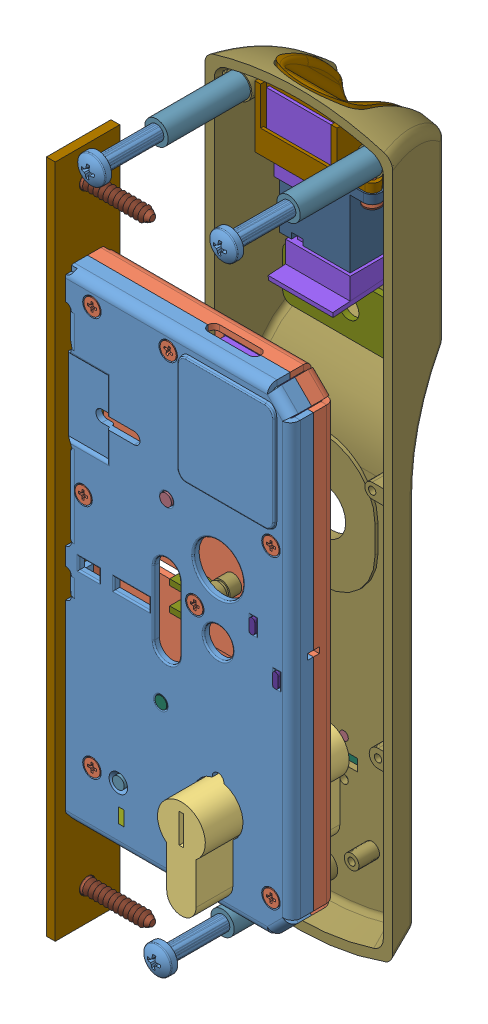
SolidWorks assembly porte, configuration Défaut. Lengths in mm.
Overall size (273.47 400 77.87).
74 component instances, 43 part files, 45 mates.
Components (placement in the parent):
- capteur-1: capteur [Défaut] at (-59.4622 -33.5309 -3.2336) x (0.307692 -0.951486 0) z (-0.951486 -0.307692 0) size (14.18 5.77 12.92)
  - piece26-1: piece26 [Défaut] at (1.6738 0.6186 2.775) size (12.75 5.77 7.15)
  - piece 28-1: piece 28 [Défaut] at (1.6738 0.6186 0.775) size (12.75 5.77 5.95)
  - piece27-2: piece27 [Défaut] at (-0.2012 0.6186 2.975) size (1 2.8 4.5)
  - piece29-1: piece29 [Défaut] at (-3.3489 0.6186 5.3357) x (0.986417 0 0.164259) z (-0.164259 0 0.986417) size (13.3 5.06 1.9)
- Assemblage9-1: Assemblage9 [Défaut] at (-68.5121 32.669 3.5) x (0 1 0) z (0 0 -1) size (37.07 29 14.01)
  - Pièce31-1: Pièce31 [Défaut] at (-136.852 -20.6482 -3) size (37.07 29 6.5)
  - Assemblage8-1: Assemblage8 [Défaut] at (10.8904 0.9488 3.6462) x (0 0 1) z (0 1 0) size (12.77 25.8 12.77)
    - piece 33-1: piece 33 [Défaut] at (-0.2667 2.2913 0) size (11 9 11)
    - piece32-1: piece32 [Défaut] at (-0.2667 2.2913 0) x (-0.176766 0 0.984253) z (-0.984253 0 -0.176766) size (11 19.8 11)
  - Pièce30-1: Pièce30 [Défaut] at (-136.852 22.3518 10) x (1 0 0) z (0 0 -1) size (37.07 29 14)
- tetiere-1: tetiere [Défaut] at (-124.6604 -27.8986 -47.7834) x (0 0 -1) z (1 0 0) size (22 230 25.2)
  - tetiere-1: tetiere [Défaut] at (-47.7834 3.4752 0) size (22 230 6)
  - Pièce37-1: Pièce37 [Défaut] at (-8.0012 83.4752 -19.368) x (1 0 0) z (0 -1 0) size (11 12 10)
  - Pièce37-2: Pièce37 [Défaut] at (-8.0012 -52.5248 -19.368) x (1 0 0) z (0 -1 0) size (11 12 10)
  - vis F90 M5-25-1: vis F90 M5-25 [PreviewCfg] at (-47.7834 107.4752 -1.3) x (0 0 1) z (-1 0 0) size (25 9.3 9.3)
  - vis F90 M5-25-2: vis F90 M5-25 [PreviewCfg] at (-47.7834 -100.5248 -1.3) x (0 0 1) z (-1 0 0) size (25 9.3 9.3)
- Assemblage5-1: Assemblage5 [Défaut] at (-67.1198 -31.1461 -5) x (0 1 0) z (0 0 1) size (150 70 16.5)
  - Pièce20-1: Pièce20 [Défaut] at (81.7227 21.0405 -3.5) x (0 0 1) z (-1 0 0) size (14 6 6)
  - Pièce20-2: Pièce20 [Défaut] at (41.7227 -13.9595 -3.5) x (0 0 1) z (-1 0 0) size (14 6 6)
  - Pièce20-3: Pièce20 [Défaut] at (24.7227 50.0405 -3.5) x (0 0 1) z (-1 0 0) size (14 6 6)
  - Pièce20-4: Pièce20 [Défaut] at (11.2227 11.9905 -3.5) x (0 0 1) z (-0.071229 0.99746 0) size (14 6 6)
  - Pièce20-5: Pièce20 [Défaut] at (-62.2773 -13.9595 -3.5) x (0 0 1) z (-1 0 0) size (14 6 6)
  - Pièce21-1: Pièce21 [Défaut] at (37.7227 21.5405 -3.5) x (0 0 1) z (-1 0 0) size (16.4 6 6)
  - Pièce23-1: Pièce23 [Défaut] at (-54.2773 38.0405 -3.5) x (0 0 1) z (-1 0 0) size (16 6 6)
  - Pièce22-2: Pièce22 [Défaut] at (-23.2773 23.5405 -3.5) x (0 0 1) z (-0.988921 -0.148442 0) size (16 6 6)
  - Pièce24-1: Pièce24 [Défaut] at (3.7227 19.5405 3) x (-1 0 0) z (0 0 -1) size (10 9 9.5)
  - Pièce25-1: Pièce25 [Défaut] at (-74.2773 -20.9595 -0.5) size (28 10 16)
  - Pièce38-1: Pièce38 [Défaut] at (65.7227 21.0405 -3.5) x (0 0 1) z (-1 0 0) size (9 6 6)
- Pièce18-1: Pièce18 [Défaut] at (-46.1604 57.5766 7.5) x (0 -1 0) z (0 0 -1) size (163.01 77.21 8.5)
- vis1-1: vis1 [ISO 7046-1 - M3 x 6 - Z --- 6C] at (-114.1604 50.5766 -7.5) x (0 0 1) z (0 -1 0) size (6 5.5 5.5)
- vis1-2: vis1 [ISO 7046-1 - M3 x 6 - Z --- 6C] at (-114.1604 -85.4234 -7.5) x (0 0 1) z (0.484646 -0.87471 0) size (6 5.5 5.5)
- vis1-3: vis1 [ISO 7046-1 - M3 x 6 - Z --- 6C] at (-53.1604 10.5766 7.5) x (0 0 -1) z (0 1 0) size (6 5.5 5.5)
- vis1-4: vis1 [ISO 7046-1 - M3 x 6 - Z --- 6C] at (-53.1604 -93.4234 7.5) x (0 0 -1) z (0 1 0) size (6 5.5 5.5)
- vis1-5: vis1 [ISO 7046-1 - M3 x 6 - Z --- 6C] at (-88.1604 50.5766 7.5) x (0 0 -1) z (-0.949467 0.313867 0) size (6 5.5 5.5)
- vis1-6: vis1 [ISO 7046-1 - M3 x 6 - Z --- 6C] at (-117.1604 -6.4234 7.5) x (0 0 -1) z (0 1 0) size (6 5.5 5.5)
- vis1-7: vis1 [ISO 7046-1 - M3 x 6 - Z --- 6C] at (-114.1604 -85.4234 7.5) x (0 0 -1) z (0 1 0) size (6 5.5 5.5)
- vis1-8: vis1 [ISO 7046-1 - M3 x 6 - Z --- 6C] at (-114.1604 50.5766 7.5) x (0 0 -1) z (0 1 0) size (6 5.5 5.5)
- vis1-9: vis1 [ISO 7046-1 - M3 x 6 - Z --- 6C] at (-79.1104 -19.9234 7.5) x (0 0 -1) z (0 1 0) size (6 5.5 5.5)
- vis2-1: vis2 [ISO 7045 - M2 x 8 - Z --- 8N] at (-61.1604 -32.4234 1.87) x (0 0 -1) z (0 1 0) size (9.57 4 4)
- vis2-2: vis2 [ISO 7045 - M2 x 8 - Z --- 8N] at (-59.1604 -38.6081 1.87) x (0 0 -1) z (0 1 0) size (9.57 4 4)
- vis5-1: vis5 [ISO 7046-1 - M2 x 4 - Z --- 4C] at (-78.6604 46.8507 -3.4464) x (0 0 -1) z (0.839549 0.543284 0) size (5 3.8 3.8)
- Pièce35-1: Pièce35 [Défaut] at (-90.6604 -54.4234 0.5) x (0 1 0) z (0 0 1) size (11 11 0.5)
- Pièce6-1: Pièce6 [Défaut] at (-90.6604 -54.4234 -2.5) x (0.802376 0.596819 0) z (0 0 1) size (8 8 3)
- Pièce13-1: Pièce13 [Défaut] at (-59.3625 -101.9234 0) size (24 12 15)
- Assemblage a3-2: Assemblage a3 [Défaut] at (-71.1604 89.3876 -33.9686) x (0 1 0) z (-1 0 0) size (249.51 77.87 69.84)
  - pièce a25-1: pièce a25 [Défaut] at (28.1889 -12.4686 0) size (57.24 25.6 22)
  - pièce a23-1: pièce a23 [Défaut] at (29.1889 -14.9686 0) x (-1 0 0) z (0 0 -1) size (32.42 29.23 38)
  - pièce a24-2: pièce a24 [Défaut] at (-4.8111 7.5314 0) x (0 0 1) z (1 0 0) size (42 16 26)
  - piece a27-1: piece a27 [B18.6.7M - M3 x 0.5 x 6 Type I Cross Recessed FHMS --6N] at (3.4889 -5.4686 -16.5) size (7 5.5 5.5)
  - piece a27-2: piece a27 [B18.6.7M - M3 x 0.5 x 6 Type I Cross Recessed FHMS --6N] at (3.4889 -5.4686 16.5) x (1 0 0) z (0 0 -1) size (7 5.5 5.5)
  - Assemblage a1-1: Assemblage a1 [Défaut] at (-110.8532 -13.9686 -2.8343) x (0 0 1) z (0 1 0) size (69.84 249.51 54.23)
    - piece a1-1: piece a1 [Défaut] at (2.8343 16.0422 0) size (69.84 249.51 28.23)
    - pièce a9-4: pièce a9 [Défaut] at (-3.5296 -48.0939 9) size (3 3 2)
    - pièce a9-5: pièce a9 [Défaut] at (0.505 -63.1512 9) x (-0.5 0.866025 0) z (0 0 1) size (3 3 2)
    - pièce a9-6: pièce a9 [Défaut] at (11.5277 -52.1285 9) x (-0.5 -0.866025 0) z (0 0 1) size (3 3 2)
    - pièce a8-1: pièce a8 [Défaut] at (25.3343 133.0422 8) x (0 0 -1) z (1 0 0) size (34 8 8)
    - pièce a8-2: pièce a8 [Défaut] at (-19.6657 133.0422 8) x (0 0 -1) z (1 0 0) size (34 8 8)
    - pièce a27-1: pièce a27 [Défaut] at (2.8343 -54.4578 11) size (22 22 2.5)
    - pièce a8-3: pièce a8 [Défaut] at (2.8343 -88.9578 8) x (0 0 -1) z (1 0 0) size (34 8 8)
    - pièce a26-1: pièce a26 [Défaut] at (2.8343 71.0422 17) size (45 18 2)
    - piece a20-1: piece a20 [ISO 7045 - M3 x 8 - Z --- 8N] at (-15.6657 104.0422 16.1) x (0 0 1) z (-1 0 0) size (10.35 5.6 5.6)
    - piece a20-2: piece a20 [ISO 7045 - M3 x 8 - Z --- 8N] at (21.3343 104.0422 16.1) x (0 0 1) z (-1 0 0) size (10.35 5.6 5.6)
    - piece a21-1: piece a21 [ISO 7045 - M3 x 6 - Z --- 6N] at (-15.6657 71.0422 14.6) x (0 0 1) z (-1 0 0) size (8.35 5.6 5.6)
    - piece a21-2: piece a21 [ISO 7045 - M3 x 6 - Z --- 6N] at (21.3343 71.0422 14.6) x (0 0 1) z (-1 0 0) size (8.35 5.6 5.6)
  - vis4-1: vis4 [ISO 7045 - M5 x 45 - Z --- 45N] at (22.1889 -63.6686 -22.5) x (0 1 0) z (0.065029 0 0.997883) size (48.63 9.5 9.5)
  - vis4-2: vis4 [ISO 7045 - M5 x 45 - Z --- 45N] at (22.1889 -63.6686 22.5) x (0 1 0) z (0.065029 0 0.997883) size (48.63 9.5 9.5)
  - vis4-3: vis4 [ISO 7045 - M5 x 45 - Z --- 45N] at (-199.8111 -63.6686 0) x (0 1 0) z (0.065029 0 0.997883) size (48.63 9.5 9.5)
- porte-2: porte [Défaut] at (23.8396 10.5766 0) size (273.47 400 40) (hidden)
- Pièce19-1: Pièce19 [Défaut] at (-46.1604 -105.4234 -7.5) x (0 1 0) z (0 0 1) size (163.01 77.21 11)
- cylindre europeen-1: cylindre europeen [Défaut] at (-71.1604 -75.9234 -2.5) x (-1 0 0) z (0 0 -1) size (16.3 33.65 49)
- vis F90 M5-60-1: vis F90 M5-60 [PreviewCfg] at (-125.9604 -95.4234 0) size (60 9.3 9.3)
- axe moteur-1: axe moteur [Défaut] at (-65.5909 21.3931 -13.2202) x (-0.984609 0 -0.17477) z (0.17477 0 -0.984609) size (5.26 10.46 5.13)
- poussoir-1: poussoir [Défaut] at (-46.1604 -106.9762 -2.2801) x (0 1 0) z (0 0 1) size (21.08 22 6)
Mates (geometry in assembly coordinates):
- Coïncidente37: coincident aligned: cone of Pièce18-1 through (-114.1604 50.5766 7.5) axis (0 0 -1); cone of vis1-8 through (-114.1604 50.5766 7.1) axis (0 0 -1)
- Coïncidente38: coincident aligned: cone of Pièce18-1 through (-88.1604 50.5766 7.5) axis (0 0 -1); cone of vis1-5 through (-88.1604 50.5766 7.1) axis (0 0 -1)
- Coïncidente39: coincident aligned: cone of Pièce18-1 through (-53.1604 10.5766 7.5) axis (0 0 -1); cone of vis1-3 through (-53.1604 10.5766 7.1) axis (0 0 -1)
- Coïncidente41: coincident aligned: cone of Pièce18-1 through (-53.1604 -93.4234 7.5) axis (0 0 -1); cone of vis1-4 through (-53.1604 -93.4234 7.1) axis (0 0 -1)
- Coïncidente42: coincident aligned: cone of Pièce18-1 through (-117.1604 -6.4234 7.5) axis (0 0 -1); cone of vis1-6 through (-117.1604 -6.4234 7.1) axis (0 0 -1)
- Coïncidente43: coincident aligned: cone of Pièce18-1 through (-114.1604 -85.4234 7.5) axis (0 0 -1); cone of vis1-7 through (-114.1604 -85.4234 7.1) axis (0 0 -1)
- Coïncidente59: coincident aligned: cone of Pièce18-1 through (-79.1104 -19.9234 7.5) axis (0 0 -1); cone of vis1-9 through (-79.1104 -19.9234 7.1) axis (0 0 -1)
- Coaxiale19: concentric aligned: cylinder of tetiere-1/Pièce37-1 through (-114.1604 50.5766 9.7426) axis (0 0 -1) radius 1.5; cylinder of vis1-1 through (-114.1604 50.5766 -13.85) axis (0 0 -1) radius 1.5
- Coaxiale21: concentric aligned: cylinder of tetiere-1/Pièce37-2 through (-114.1604 -85.4234 9.7426) axis (0 0 -1) radius 1.5; cylinder of vis1-2 through (-114.1604 -85.4234 -13.85) axis (0 0 -1) radius 1.5
- Coaxiale24: concentric aligned: cylinder of Assemblage5-1/Pièce20-2 through (-53.1604 10.5766 5.5) axis (0 0 1) radius 1.25; cylinder of vis1-3 through (-53.1604 10.5766 13.85) axis (0 0 1) radius 1.5
- Coaxiale25: concentric aligned: cylinder of Assemblage5-1/Pièce20-5 through (-53.1604 -93.4234 5.5) axis (0 0 1) radius 1.25; cylinder of vis1-4 through (-53.1604 -93.4234 13.85) axis (0 0 1) radius 1.5
- Coaxiale23: concentric aligned: cylinder of Assemblage5-1/Pièce20-1 through (-88.1604 50.5766 5.5) axis (0 0 1) radius 1.25; cylinder of vis1-5 through (-88.1604 50.5766 13.85) axis (0 0 1) radius 1.5
- Coaxiale26: concentric aligned: cylinder of Assemblage5-1/Pièce20-3 through (-117.1604 -6.4234 5.5) axis (0 0 1) radius 1.25; cylinder of vis1-6 through (-117.1604 -6.4234 13.85) axis (0 0 1) radius 1.5
- Coaxiale27: concentric anti-aligned: cylinder of tetiere-1/Pièce37-2 through (-114.1604 -85.4234 9.7426) axis (0 0 -1) radius 1.5; cylinder of vis1-7 through (-114.1604 -85.4234 13.85) axis (0 0 1) radius 1.5
- Coaxiale22: concentric anti-aligned: cylinder of tetiere-1/Pièce37-1 through (-114.1604 50.5766 9.7426) axis (0 0 -1) radius 1.5; cylinder of vis1-8 through (-114.1604 50.5766 13.85) axis (0 0 1) radius 1.5
- Coaxiale33: concentric aligned: cylinder of Assemblage5-1/Pièce20-4 through (-79.1104 -19.9234 5.5) axis (0 0 1) radius 1.25; cylinder of vis1-9 through (-79.1104 -19.9234 13.85) axis (0 0 1) radius 1.5
- Coaxiale29: concentric aligned: cylinder of capteur-1/piece26-1 through (-61.1604 -32.4234 -5.5) axis (0 0 1) radius 1; cylinder of vis2-1 through (-61.1604 -32.4234 27.27) axis (0 0 1) radius 1
- Coïncidente52: coincident anti-aligned: plane of capteur-1/piece26-1 through (-60.6947 -28.9885 0.27) normal (0 0 1); plane of vis2-1 through (-62.1604 -32.4234 0.27) normal (0 0 -1)
- Coaxiale30: concentric aligned: cylinder of capteur-1/piece26-1 through (-59.1604 -38.6081 -5.5) axis (0 0 1) radius 1; cylinder of vis2-2 through (-59.1604 -38.6081 27.27) axis (0 0 1) radius 1
- Coïncidente53: coincident anti-aligned: plane of capteur-1/piece26-1 through (-60.6947 -28.9885 0.27) normal (0 0 1); plane of vis2-2 through (-60.1604 -38.6081 0.27) normal (0 0 -1)
- Coïncidente58: coincident aligned: plane of Assemblage9-1/Pièce30-1 through (-53.1604 18.2833 -4.5) normal (0 0 1); circle of vis5-1
- Coaxiale6: concentric anti-aligned: cylinder of Assemblage5-1/Pièce22-2 through (-90.6604 -54.4234 7.5) axis (0 0 1) radius 2; cylinder of Pièce35-1 through (-90.6604 -54.4234 1) axis (0 0 -1) radius 2
- Coïncidente8: coincident anti-aligned: plane of Assemblage5-1/Pièce22-2 through (-93.6271 -54.8688 -2.5) normal (0 0 1); plane of Pièce6-1 through (-90.6604 -54.4234 -2.5) normal (0 0 -1)
- Coaxiale9: concentric anti-aligned: cylinder of Assemblage5-1/Pièce22-2 through (-90.6604 -54.4234 7.5) axis (0 0 1) radius 2; cylinder of Pièce6-1 through (-90.6604 -54.4234 0.5) axis (0 0 -1) radius 2
- Coïncidente9: coincident anti-aligned: plane of Pièce6-1 through (-90.6604 -54.4234 0.5) normal (0 0 1); plane of Pièce35-1 through (-90.6604 -54.4234 0.5) normal (0 0 -1)
- Coïncidente1: coincident anti-aligned: plane of porte-2 through (-123.1604 -139.4234 -11) normal (-1 0 0); plane of tetiere-1/tetiere-1 through (-123.1604 -139.4234 11) normal (1 0 0)
- Coïncidente2: coincident anti-aligned: plane of porte-2 through (-123.1604 90.5766 -11) normal (0 0 1); plane of tetiere-1/tetiere-1 through (-123.1604 90.5766 -11) normal (0 0 -1)
- Coïncidente3: coincident anti-aligned: plane of porte-2 through (-123.1604 90.5766 -11) normal (0 -1 0); plane of tetiere-1/tetiere-1 through (-123.1604 90.5766 11) normal (0 1 0)
- Coïncidente24: coincident anti-aligned: plane of porte-2 through (88.5835 12.6562 -20) normal (0 0 -1); plane of Assemblage a3-2/Assemblage a1-1/piece a1-1 through (-71.1604 23.5766 -20) normal (0 0 1)
- Coaxiale15: concentric aligned: cylinder of porte-2 through (-93.6604 111.5766 -20) axis (0 0 1) radius 5; cylinder of Assemblage a3-2/Assemblage a1-1/pièce a8-1 through (-93.6604 111.5766 6) axis (0 0 1) radius 4
- Coaxiale16: concentric aligned: cylinder of porte-2 through (-71.1604 -110.4234 -20) axis (0 0 1) radius 5; cylinder of Assemblage a3-2/Assemblage a1-1/pièce a8-3 through (-71.1604 -110.4234 6) axis (0 0 1) radius 4
- Coaxiale15: concentric aligned: cone of vis1-2 through (-114.1604 -85.4234 -7.1) axis (0 0 1); cone of Pièce19-1 through (-114.1604 -85.4234 -7.5) axis (0 0 1)
- Coïncidente49: coincident aligned: plane of vis1-2 through (-114.1604 -85.4234 -7.5) normal (0 0 -1); plane of Pièce19-1 through (28.3396 -23.9234 -7.5) normal (0 0 -1)
- Coaxiale16: concentric aligned: cone of vis1-1 through (-114.1604 50.5766 -7.1) axis (0 0 1); cone of Pièce19-1 through (-114.1604 50.5766 -7.5) axis (0 0 1)
- Coïncidente54: coincident aligned: cone of tetiere-1/tetiere-1 through (-126.1604 -95.4234 0) axis (1 0 0); cone of vis F90 M5-60-1 through (-125.6104 -95.4234 0) axis (1 0 0)
- Parallèle6: parallel aligned: plane of tetiere-1/tetiere-1 through (-123.1604 90.5766 11) normal (0 0 1); plane of vis F90 M5-60-1 through (-123.4479 -95.4234 -0.5) normal (0 0 1)
- Coaxiale9: concentric aligned: cylinder of Assemblage9-1/Assemblage8-1/piece32-1 through (-67.5633 26.0507 0.1204) axis (0 1 0) radius 3; cylinder of axe moteur-1 through (-67.5633 16.0507 0.1204) axis (0 1 0) radius 1.25
- Coïncidente7: coincident anti-aligned: plane of axe moteur-1 through (-67.5633 26.0507 0.1204) normal (0 1 0); plane of Assemblage9-1/Assemblage8-1/piece32-1 through (-67.5633 26.0507 0.1204) normal (0 -1 0)
- Distance8: distance = 3 mm anti-aligned: plane of poussoir-1 through (-60.6604 15.7833 3.7199) normal (0 -1 0); plane of Assemblage9-1/Pièce30-1 through (-58.6604 18.7833 15.5242) normal (0 1 0)
- Parallèle5: parallel anti-aligned: plane of Assemblage9-1/Pièce30-1 through (-76.6604 15.2833 -2.5) normal (0 0 1); plane of poussoir-1 through (-60.6604 15.7833 -2.2801) normal (0 0 -1)
- Coïncidente53: coincident anti-aligned: plane of Assemblage9-1/Pièce30-1 through (-79.6604 15.2833 0) normal (1 0 0); plane of poussoir-1 through (-79.6604 36.8622 3.7199) normal (-1 0 0)
- Tangent12: tangent: face of axe moteur-1; cylinder of poussoir-1 through (-57.6604 21.7592 1.7766) axis (-1 0 0) radius 0.2
- Coïncidente60: coincident anti-aligned: plane of capteur-1/piece 28-1 through (-67.3075 -31.127 -5.5) normal (0 0 -1); plane of Pièce19-1 through (28.3396 -23.9234 -5.5) normal (0 0 1)
- Coaxiale34: concentric anti-aligned: cylinder of vis2-1 through (-61.1604 -32.4234 27.27) axis (0 0 1) radius 1; cylinder of Pièce19-1 through (-61.1604 -32.4234 0.001) axis (0 0 -1) radius 1
- Coaxiale35: concentric anti-aligned: cylinder of vis2-2 through (-59.1604 -38.6081 27.27) axis (0 0 1) radius 1; cylinder of Pièce19-1 through (-59.1604 -38.6081 0.001) axis (0 0 -1) radius 1
